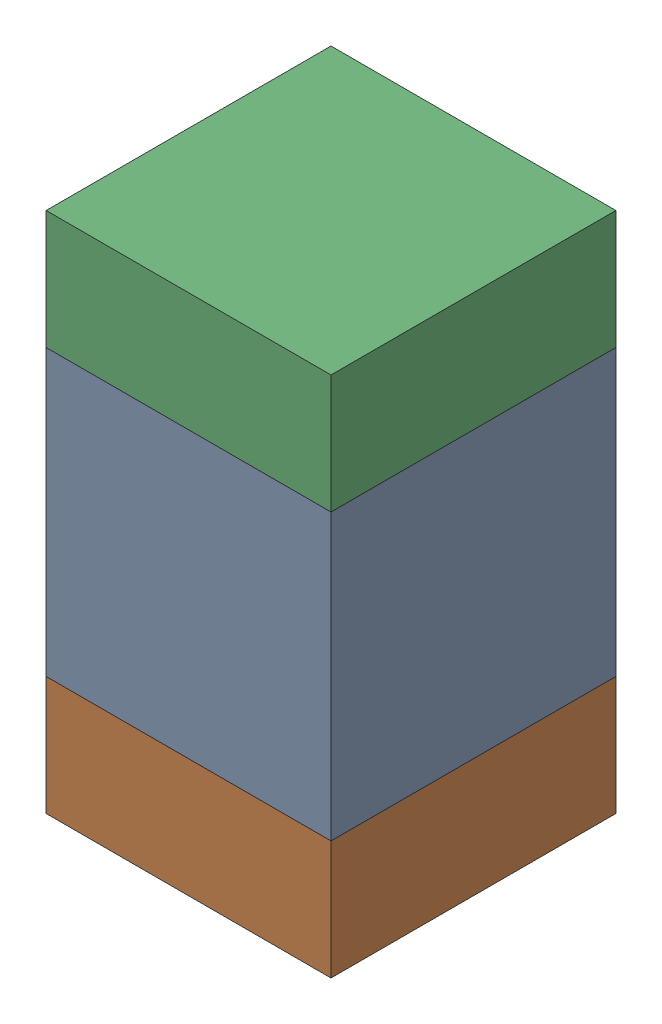
SolidWorks assembly C430PCB, configuration Default. Lengths in mm.
Overall size (0.6 1.1 0.6).
6 component instances, 2 part files, 0 mates.
Components (placement in the parent):
- 761606048-1: 761606048 [Default] at (122.4 103.7 -2.2638) size (0.6 0.6 0.6)
  - Extruded_9-1: Extruded_9 [Default] at origin size (0.6 0.6 0.6)
- 854785296-1: 854785296 [Default] at (122.4 103.275 -2.2638) size (0.6 0.25 0.6)
  - Extruded_10-1: Extruded_10 [Default] at origin size (0.6 0.25 0.6)
- 854785296-2: 854785296 [Default] at (122.4 104.125 -2.2638) size (0.6 0.25 0.6)
  - Extruded_10-1: Extruded_10 [Default] at origin size (0.6 0.25 0.6)
